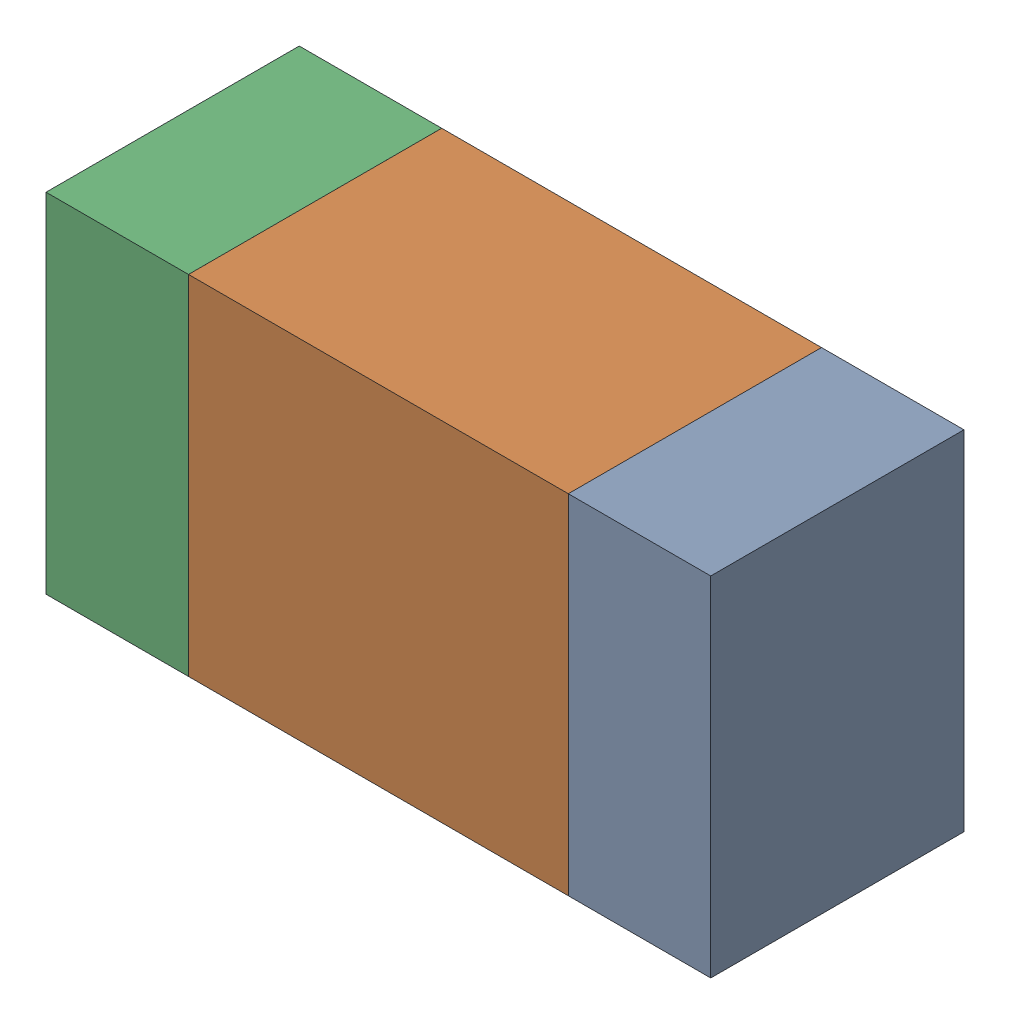
SolidWorks assembly R306_1PCB, configuration Default. Lengths in mm.
Overall size (1.05 0.55 0.4).
6 component instances, 2 part files, 0 mates.
Components (placement in the parent):
- 854785432-1: 854785432 [Default] at (141.3126 120.7001 0) size (0.22 0.55 0.4)
  - Extruded-1: Extruded [Default] at origin size (0.22 0.55 0.4)
- 854785568-1: 854785568 [Default] at (140.9001 120.7001 0) size (0.6 0.55 0.4)
  - Extruded_2-1: Extruded_2 [Default] at origin size (0.6 0.55 0.4)
- 854785432-2: 854785432 [Default] at (140.4876 120.7001 0) size (0.22 0.55 0.4)
  - Extruded-1: Extruded [Default] at origin size (0.22 0.55 0.4)
